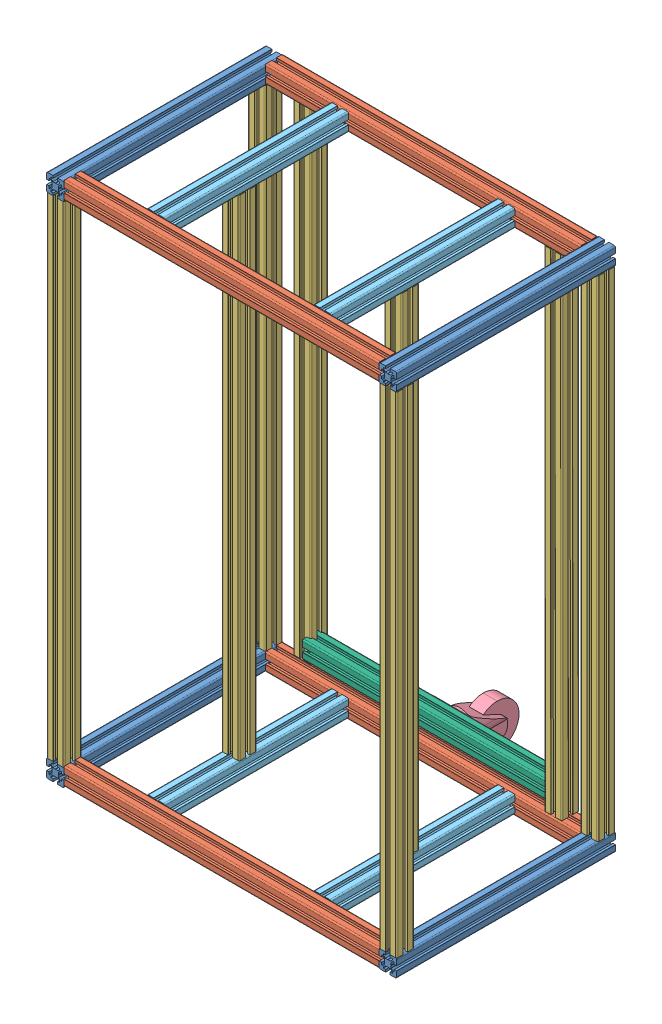
SolidWorks assembly CarBody_Caster_Rev3, configuration ﾃﾞﾌｫﾙﾄ. Lengths in mm.
Overall size (800 1230.74 644.76).
22 component instances, 6 part files, 37 mates.
Components (placement in the parent):
- Flame_500mm-1: Flame_500mm [ﾃﾞﾌｫﾙﾄ] at origin size (40 40 500)
- Flame_500mm-2: Flame_500mm [ﾃﾞﾌｫﾙﾄ] at (760 3 0) size (40 40 500)
- Flame_720mm-1: Flame_720mm [ﾃﾞﾌｫﾙﾄ] at (70 103 30) x (0 0 -1) z (-1 0 0) size (40 40 720)
- Flame_720mm-2: Flame_720mm [ﾃﾞﾌｫﾙﾄ] at (790 0 -430) x (0 0 -1) z (1 0 0) size (40 40 720)
- Flame_1120mm-1: Flame_1120mm [ﾃﾞﾌｫﾙﾄ] at (100 70 -70) x (0 0 1) z (0 -1 0) size (40 40 1120)
- Flame_1120mm-2: Flame_1120mm [ﾃﾞﾌｫﾙﾄ] at (0 70 -530) x (1 0 0) z (0 -1 0) size (40 40 1120)
- Flame_1120mm-3: Flame_1120mm [ﾃﾞﾌｫﾙﾄ] at (760 73 -530) x (1 0 0) z (0 -1 0) size (40 40 1120)
- Flame_1120mm-4: Flame_1120mm [ﾃﾞﾌｫﾙﾄ] at (760 73 -70) x (1 0 0) z (0 -1 0) size (40 40 1120)
- Flame_500mm-3: Flame_500mm [ﾃﾞﾌｫﾙﾄ] at (0 1160 0) size (40 40 500)
- Flame_500mm-4: Flame_500mm [ﾃﾞﾌｫﾙﾄ] at (760 1163 0) size (40 40 500)
- Flame_720mm-3: Flame_720mm [ﾃﾞﾌｫﾙﾄ] at (789.9911 1162.9588 -430.036) x (0.000018 0.000589 -1) z (1 -0.000124 0.000018) size (40 40 720)
- Flame_720mm-4: Flame_720mm [ﾃﾞﾌｫﾙﾄ] at (790 1163 30) x (0 0 -1) z (1 0 0) size (40 40 720)
- pms_100uwb_Caster-1: pms_100uwb_Caster [ﾃﾞﾌｫﾙﾄ] at (448.9887 84.3538 -500.7556) x (0 1 0) z (1 0 0) size (129.5 144 95)
- Flame_420mm-1: Flame_420mm [ﾃﾞﾌｫﾙﾄ] at (570 3 -40) size (40 40 420)
- Flame_420mm-2: Flame_420mm [ﾃﾞﾌｫﾙﾄ] at (190 3 -40) size (40 40 420)
- Flame_420mm-3: Flame_420mm [ﾃﾞﾌｫﾙﾄ] at (570 1163 -40) size (40 40 420)
- Flame_420mm-4: Flame_420mm [ﾃﾞﾌｫﾙﾄ] at (190 1163 -40) size (40 40 420)
- Flame_1120mm-6: Flame_1120mm [ﾃﾞﾌｫﾙﾄ] at (189.9606 73 -279.9781) x (1 0 -0.000563) z (0 -1 0) size (40 40 1120)
- Flame_1120mm-7: Flame_1120mm [ﾃﾞﾌｫﾙﾄ] at (570 73 -271.5566) x (1 0 0) z (0 -1 0) size (40 40 1120)
- Flame_1120mm-8: Flame_1120mm [ﾃﾞﾌｫﾙﾄ] at (676.8578 73.0319 -530.6799) x (1 -0.000124 0.000018) z (-0.000124 -1 -0.000589) size (40 40 1120)
- Flame_1120mm-9: Flame_1120mm [ﾃﾞﾌｫﾙﾄ] at (92.5373 85.0776 -541.0814) x (1 0 0) z (0 -1 0) size (40 40 1120)
- Flame_554mm-3: Flame_554mm [ﾃﾞﾌｫﾙﾄ] at (708.1912 65.8192 -430.4592) x (0 0 -1) z (1 0 0) size (40 40 554)
Mates (geometry in assembly coordinates):
- 一致1: coincident aligned: line of Flame_500mm-1 through (11.7 70 67) axis (0 0 -1); line of Flame_720mm-1 through (70 70 0) axis (0 -1 0)
- 一致2: coincident: point of Flame_500mm-2; unknown of Flame_720mm-1
- 一致3: coincident: unknown of Flame_500mm-1; unknown of Flame_720mm-2
- 一致4: coincident: unknown of Flame_500mm-1; unknown of Flame_1120mm-1
- 一致6: coincident: unknown of Flame_500mm-1; unknown of Flame_1120mm-2
- 一致7: coincident: unknown of Flame_500mm-2; unknown of Flame_1120mm-3
- 一致8: coincident: unknown of Flame_500mm-2; unknown of Flame_1120mm-4
- 一致10: coincident: unknown of Flame_1120mm-2; unknown of Flame_500mm-3
- 一致11: coincident: unknown of Flame_1120mm-4; unknown of Flame_500mm-4
- 一致14: coincident: unknown of Flame_500mm-4; unknown of Flame_720mm-4
- 一致16: coincident: unknown of Flame_500mm-4; unknown of Flame_720mm-3
- 垂直1: perpendicular: plane of Flame_720mm-1 through (790 36 -40) normal (0 0 -1); plane of Flame_420mm-1 through (640 36 -460) normal (1 0 0)
- 一致28: coincident anti-aligned: plane of Flame_720mm-1 through (790 36 -40) normal (0 0 -1); plane of Flame_420mm-1 through (603 70 -40) normal (0 0 1)
- 一致29: coincident: line of Flame_720mm-1 through (790 36 -40) axis (-1 0 0); point of Flame_420mm-1
- 距離2: distance = 150 mm anti-aligned: plane of Flame_420mm-1 through (640 36 -460) normal (1 0 0); plane of Flame_500mm-2 through (790 36 -500) normal (-1 0 0)
- 一致30: coincident anti-aligned: plane of Flame_720mm-1 through (790 36 -40) normal (0 0 -1); plane of Flame_420mm-2 through (223 70 -40) normal (0 0 1)
- 距離3: distance = 150 mm anti-aligned: plane of Flame_420mm-2 through (220 36 -460) normal (-1 0 0); plane of Flame_500mm-1 through (70 33 -500) normal (1 0 0)
- 一致33: coincident anti-aligned: plane of Flame_720mm-4 through (70 1230 -40) normal (0 0 -1); plane of Flame_420mm-3 through (603 1230 -40) normal (0 0 1)
- 距離4: distance = 150 mm anti-aligned: plane of Flame_420mm-3 through (640 1230 -460) normal (1 0 0); plane of Flame_500mm-4 through (790 1230 -500) normal (-1 0 0)
- 一致36: coincident anti-aligned: plane of Flame_720mm-4 through (70 1230 -40) normal (0 0 -1); plane of Flame_420mm-4 through (223 1230 -40) normal (0 0 1)
- 距離5: distance = 150 mm anti-aligned: plane of Flame_420mm-4 through (220 1230 -460) normal (-1 0 0); plane of Flame_500mm-3 through (70 1227 -500) normal (1 0 0)
- 平行1: parallel anti-aligned: line of Flame_720mm-1 through (790 36 -40) axis (-1 0 0); line of Flame_420mm-1 through (603 33 -40) axis (1 0 0)
- 一致44: coincident: line of Flame_720mm-1 through (790 36 -40) axis (-1 0 0); point of Flame_420mm-2
- 一致45: coincident anti-aligned: plane of Flame_420mm-2 through (245.3 73 -460) normal (0 1 0); plane of Flame_1120mm-6 through (222.9983 73 -212.9967) normal (0 -1 0)
- 距離9: distance = 250 mm: unknown of Flame_1120mm-6; unknown of Flame_420mm-2
- 一致55: coincident aligned: line of Flame_720mm-2 through (70 33 -460) axis (1 0 0); line of Flame_420mm-1 through (625.3 33 -460) axis (1 0 0)
- 一致59: coincident: line of Flame_420mm-2 through (257 73 -460) axis (0 0 1); point of Flame_1120mm-6
- 一致61: coincident: line of Flame_720mm-3 through (70 1230.0657 -460.0096) axis (1 -0.000124 0.000018); point of Flame_420mm-3
- 一致66: coincident: line of Flame_720mm-4 through (70 1230 -40) axis (1 0 0); point of Flame_420mm-4
- 一致77: coincident: line of Flame_720mm-4 through (70 1230 -40) axis (1 0 0); point of Flame_420mm-3
- 一致78: coincident: line of Flame_720mm-4 through (70 1230 -40) axis (1 0 0); point of Flame_420mm-3
- 一致80: coincident anti-aligned: plane of Flame_420mm-1 through (625.3 73 -460) normal (0 1 0); plane of Flame_1120mm-7 through (603 73 -204.5566) normal (0 -1 0)
- 一致88: coincident: line of Flame_420mm-1 through (637 73 -460) axis (0 0 1); point of Flame_1120mm-7
- 一致89: coincident: line of Flame_420mm-3 through (603 1193 -460) axis (0 0 1); point of Flame_1120mm-7
- 一致107: coincident anti-aligned: plane of Flame_720mm-3 through (69.9955 1193.0675 -463.0314) normal (-0.000124 -1 -0.000589); plane of Flame_1120mm-8 through (709.9955 1192.9881 -463.0198) normal (0.000124 1 0.000589)
- 距離12: distance = 43 mm: line of Flame_720mm-3 through (789.9955 1192.9782 -463.0184) axis (0.000018 0.000589 -1); line of Flame_1120mm-8 through (746.9955 1192.9835 -463.0191) axis (0.000018 0.000589 -1)
- 一致110: coincident: line of Flame_720mm-3 through (69.9961 1193.0875 -497.0314) axis (1 -0.000124 0.000018); point of Flame_1120mm-8
